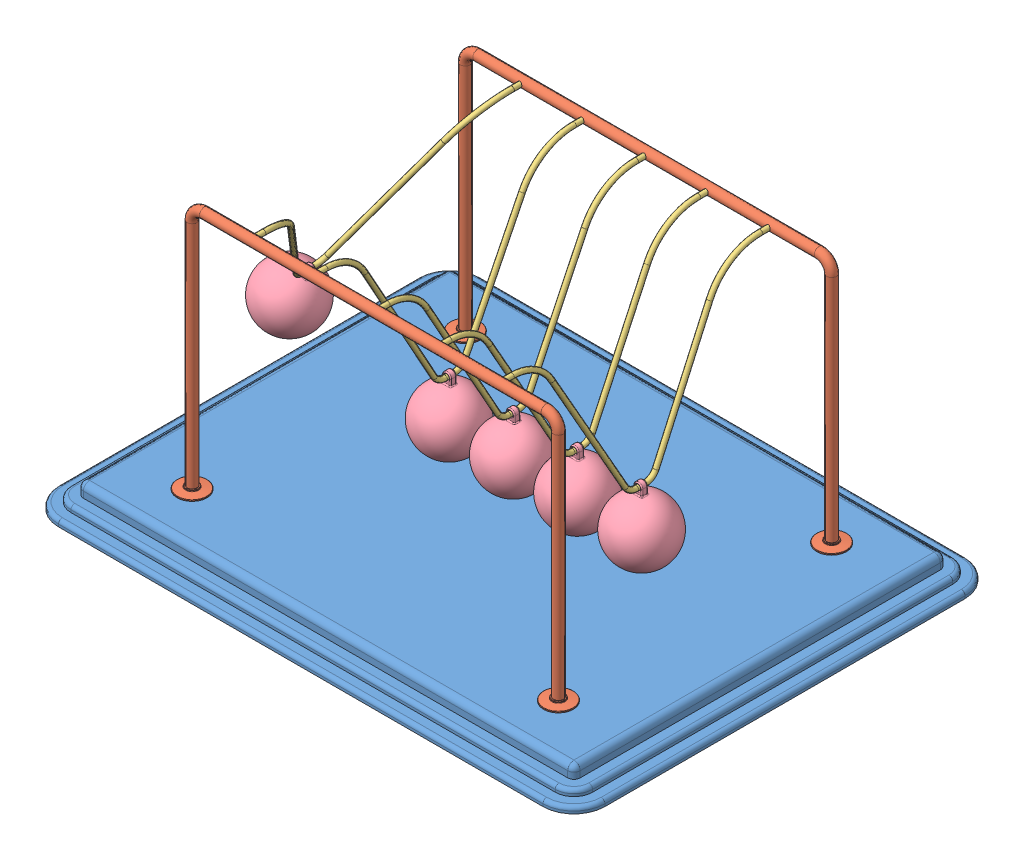
SolidWorks assembly Newtons Cradle NewtonsCradle 0234, configuration Default. Lengths in mm.
Overall size (440 222 340).
13 component instances, 4 part files, 34 mates.
Components (placement in the parent):
- Base NewtonsCradle 0234-1: Base NewtonsCradle 0234 [Default] at (-16.2968 -4.1587 11.425) size (440 20 340)
- frame NewtonsCradle 0234-1: frame NewtonsCradle 0234 [Default] at (-16.2968 144.4547 -98.575) size (319 202 24)
- frame NewtonsCradle 0234-2: frame NewtonsCradle 0234 [Default] at (-16.2968 144.4547 121.425) x (-1 0 0) z (0 0 -1) size (319 202 24)
- Hanging thing NewtonsCradle 0234-1: Hanging thing NewtonsCradle 0234 [Default] at (-157.6326 134.1825 11.425) x (0 0 1) z (-0.859985 0.510319 0) size (220 129 4)
- Hanging thing NewtonsCradle 0234-2: Hanging thing NewtonsCradle 0234 [Default] at (-66.576 122.8418 11.425) x (0 0 1) z (-0.999994 0.003446 0) size (220 129 4)
- Hanging thing NewtonsCradle 0234-3: Hanging thing NewtonsCradle 0234 [Default] at (-15.6923 122.8436 11.425) x (0 0 1) z (-0.999972 -0.007464 0) size (220 129 4)
- Hanging thing NewtonsCradle 0234-4: Hanging thing NewtonsCradle 0234 [Default] at (35.2213 122.8555 11.425) x (0 0 1) z (-0.999824 -0.018742 0) size (220 129 4)
- Hanging thing NewtonsCradle 0234-5: Hanging thing NewtonsCradle 0234 [Default] at (86.0287 122.8747 11.425) x (0 0 1) z (-0.999588 -0.028711 0) size (220 129 4)
- Sphere NewtonsCradle 0234-1: Sphere NewtonsCradle 0234 [Default] at (-195.3962 70.5436 11.425) x (0.859985 -0.510319 0) z (0 0 1) size (50 58.5 50)
- Sphere NewtonsCradle 0234-2: Sphere NewtonsCradle 0234 [Default] at (88.1533 48.9052 11.425) x (0.999588 0.028711 0) z (0 0 1) size (50 58.5 50)
- Sphere NewtonsCradle 0234-3: Sphere NewtonsCradle 0234 [Default] at (-15.14 48.8456 11.425) x (0.999972 0.007464 0) z (0 0 1) size (50 58.5 50)
- Sphere NewtonsCradle 0234-4: Sphere NewtonsCradle 0234 [Default] at (36.6081 48.8685 11.425) x (0.999824 0.018742 0) z (0 0 1) size (50 58.5 50)
- Sphere NewtonsCradle 0234-5: Sphere NewtonsCradle 0234 [Default] at (-66.831 48.8422 11.425) x (0.999994 -0.003446 0) z (0 0 1) size (50 58.5 50)
Mates (geometry in assembly coordinates):
- Coincident1: coincident anti-aligned: plane of Base-1 through (-211.2968 5.8413 156.425) normal (0 1 0); plane of frame-2 through (-175.7968 5.8413 121.425) normal (0 -1 0)
- Coincident2: coincident anti-aligned: plane of Base-1 through (-211.2968 5.8413 156.425) normal (0 1 0); plane of frame-1 through (143.2032 5.8413 -98.575) normal (0 -1 0)
- Concentric1: concentric anti-aligned: cylinder of frame-1 through (-116.2968 203.8413 -94.575) axis (0 0 -1) radius 2; cylinder of frame-2 through (-116.2968 203.8413 117.425) axis (0 0 1) radius 2
- Concentric2: concentric anti-aligned: cylinder of frame-1 through (83.7032 203.8413 -94.575) axis (0 0 -1) radius 2; cylinder of frame-2 through (83.7032 203.8413 117.425) axis (0 0 1) radius 2
- Distance1: distance = 60 mm: plane of frame-1 through (-16.2968 144.4547 -98.575) normal (0 0 1); line of Base-1 through (-211.2968 -12.1587 -158.575) axis (1 0 0)
- Distance2: distance = 60 mm: line of Base-1 through (178.7032 -12.1587 181.425) axis (-1 0 0); plane of frame-2 through (-16.2968 144.4547 121.425) normal (0 0 -1)
- Distance3: distance = 220 mm: plane of frame-2 through (-16.2968 144.4547 121.425) normal (-1 0 0); line of Base-1 through (-236.2968 -12.1587 156.425) axis (0 0 -1)
- Concentric3: concentric anti-aligned: cylinder of frame-1 through (-116.2968 203.8413 -94.575) axis (0 0 -1) radius 2; cylinder of Hanging thing-1 through (-116.2968 203.8413 111.425) axis (0 0 1) radius 2
- Concentric4: concentric anti-aligned: cylinder of frame-1 through (-116.2968 203.8413 -94.575) axis (0 0 -1) radius 2; cylinder of Hanging thing-1 through (-116.2968 203.8413 -98.575) axis (0 0 1) radius 2
- Concentric5: concentric aligned: cylinder of frame-2 through (-66.2968 203.8413 117.425) axis (0 0 1) radius 2; cylinder of Hanging thing-2 through (-66.2968 203.8413 111.425) axis (0 0 1) radius 2
- Concentric6: concentric aligned: cylinder of frame-2 through (-16.2968 203.8413 117.425) axis (0 0 1) radius 2; cylinder of Hanging thing-3 through (-16.2968 203.8413 111.425) axis (0 0 1) radius 2
- Concentric7: concentric aligned: cylinder of frame-2 through (33.7032 203.8413 117.425) axis (0 0 1) radius 2; cylinder of Hanging thing-4 through (33.7032 203.8413 111.425) axis (0 0 1) radius 2
- Concentric8: concentric aligned: cylinder of frame-2 through (83.7032 203.8413 117.425) axis (0 0 1) radius 2; cylinder of Hanging thing-5 through (83.7032 203.8413 111.425) axis (0 0 1) radius 2
- Coincident5: coincident anti-aligned: plane of frame-2 through (83.7032 203.8413 121.425) normal (0 0 -1); plane of Hanging thing-5 through (83.7032 203.8413 121.425) normal (0 0 1)
- Coincident6: coincident anti-aligned: plane of frame-2 through (33.7032 203.8413 121.425) normal (0 0 -1); plane of Hanging thing-4 through (33.7032 203.8413 121.425) normal (0 0 1)
- Coincident7: coincident anti-aligned: plane of frame-2 through (-16.2968 203.8413 121.425) normal (0 0 -1); plane of Hanging thing-3 through (-16.2968 203.8413 121.425) normal (0 0 1)
- Coincident8: coincident anti-aligned: plane of frame-2 through (-66.2968 203.8413 121.425) normal (0 0 -1); plane of Hanging thing-2 through (-66.2968 203.8413 121.425) normal (0 0 1)
- Coincident9: coincident anti-aligned: plane of frame-2 through (-116.2968 203.8413 121.425) normal (0 0 -1); plane of Hanging thing-1 through (-116.2968 203.8413 121.425) normal (0 0 1)
- Concentric9: concentric anti-aligned: cylinder of Hanging thing-1 through (-117.0163 78.8434 7.925) axis (0 0 1) radius 2; cylinder of Sphere-1 through (-117.0163 78.8434 13.925) axis (0 0 -1) radius 2
- Concentric13: concentric anti-aligned: cylinder of Hanging thing-2 through (-66.7276 78.842 7.925) axis (0 0 1) radius 2; cylinder of Sphere-5 through (-66.7276 78.842 13.925) axis (0 0 -1) radius 2
- Concentric15: concentric anti-aligned: cylinder of Hanging thing-3 through (-15.3639 78.8448 7.925) axis (0 0 1) radius 2; cylinder of Sphere-3 through (-15.3639 78.8448 13.925) axis (0 0 -1) radius 2
- Concentric16: concentric anti-aligned: cylinder of Hanging thing-5 through (87.292 78.8928 7.925) axis (0 0 1) radius 2; cylinder of Sphere-2 through (87.292 78.8928 13.925) axis (0 0 -1) radius 2
- Concentric17: concentric anti-aligned: cylinder of Hanging thing-4 through (36.0459 78.8632 7.925) axis (0 0 1) radius 2; cylinder of Sphere-4 through (36.0459 78.8632 13.925) axis (0 0 -1) radius 2
- Parallel1: parallel anti-aligned: plane of Hanging thing-1; plane of Sphere-1
- Coincident22: coincident anti-aligned: plane of Hanging thing-1; plane of Sphere-1
- Coincident12: coincident aligned: plane of Hanging thing-2 through (-66.576 122.8418 11.425) normal (0 0 1); plane of Sphere-5 through (-66.831 48.8422 11.425) normal (0 0 1)
- Coincident10: coincident aligned: plane of Hanging thing-1 through (-116.763 122.8426 11.425) normal (0 0 1); plane of Sphere-1 through (-118.5806 48.8842 11.425) normal (0 0 1)
- Coincident13: coincident anti-aligned: plane of Hanging thing-2 through (-66.576 122.8418 11.425) normal (-0.999994 0.003446 0); plane of Sphere-5 through (-66.831 48.8422 11.425) normal (0.999994 -0.003446 0)
- Coincident14: coincident anti-aligned: plane of Hanging thing-3 through (-15.6923 122.8436 11.425) normal (-0.999972 -0.007464 0); plane of Sphere-3 through (-15.14 48.8456 11.425) normal (0.999972 0.007464 0)
- Coincident15: coincident aligned: plane of Hanging thing-3 through (-15.6923 122.8436 11.425) normal (0 0 1); plane of Sphere-3 through (-15.14 48.8456 11.425) normal (0 0 1)
- Coincident18: coincident aligned: plane of Hanging thing-4 through (35.2213 122.8555 11.425) normal (0 0 1); plane of Sphere-4 through (36.6081 48.8685 11.425) normal (0 0 1)
- Coincident19: coincident anti-aligned: plane of Hanging thing-4 through (35.2213 122.8555 11.425) normal (-0.999824 -0.018742 0); plane of Sphere-4 through (36.6081 48.8685 11.425) normal (0.999824 0.018742 0)
- Coincident20: coincident anti-aligned: plane of Hanging thing-5 through (86.0287 122.8747 11.425) normal (-0.999588 -0.028711 0); plane of Sphere-2 through (88.1533 48.9052 11.425) normal (0.999588 0.028711 0)
- Coincident21: coincident aligned: plane of Hanging thing-5 through (86.0287 122.8747 11.425) normal (0 0 1); plane of Sphere-2 through (88.1533 48.9052 11.425) normal (0 0 1)
